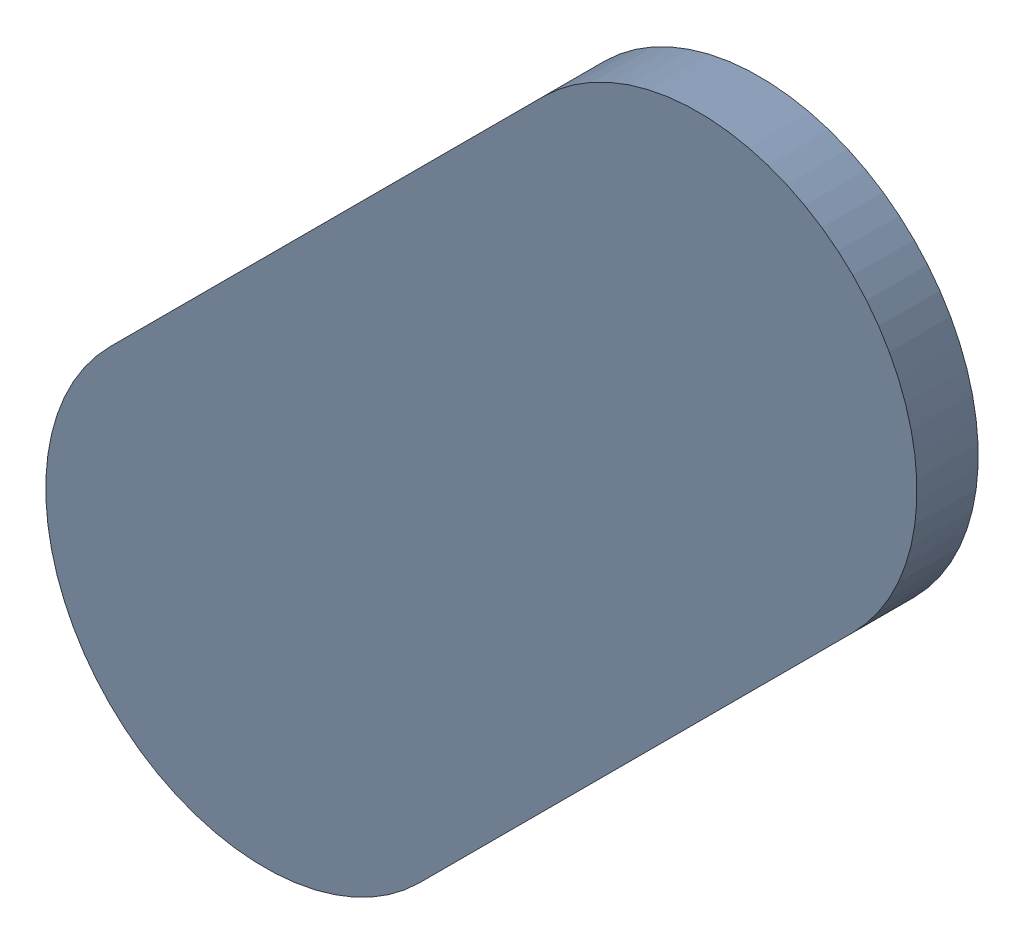
SolidWorks assembly Track (18.353mm,56.749mm)(18.605mm,57mm) on Top Layer, configuration Predeterminado. Lengths in mm.
Overall size (0.51 0.51 0.04).
2 component instances, 1 part files, 0 mates.
Components (placement in the parent):
- Track (18.353mm,56.749mm)(18.605mm,57mm) on Top Layer-1-1: Track (18.353mm,56.749mm)(18.605mm,57mm) on Top Layer-1 [Predeterminado] at (-68.317 -44.187 -0.0457) size (0.51 0.51 0.04)
  - Track (18.353mm,56.749mm)(18.605mm,57mm) on Top Layer-Part-1-1: Track (18.353mm,56.749mm)(18.605mm,57mm) on Top Layer-Part-1 [Predeterminado] at origin size (0.51 0.51 0.04)
